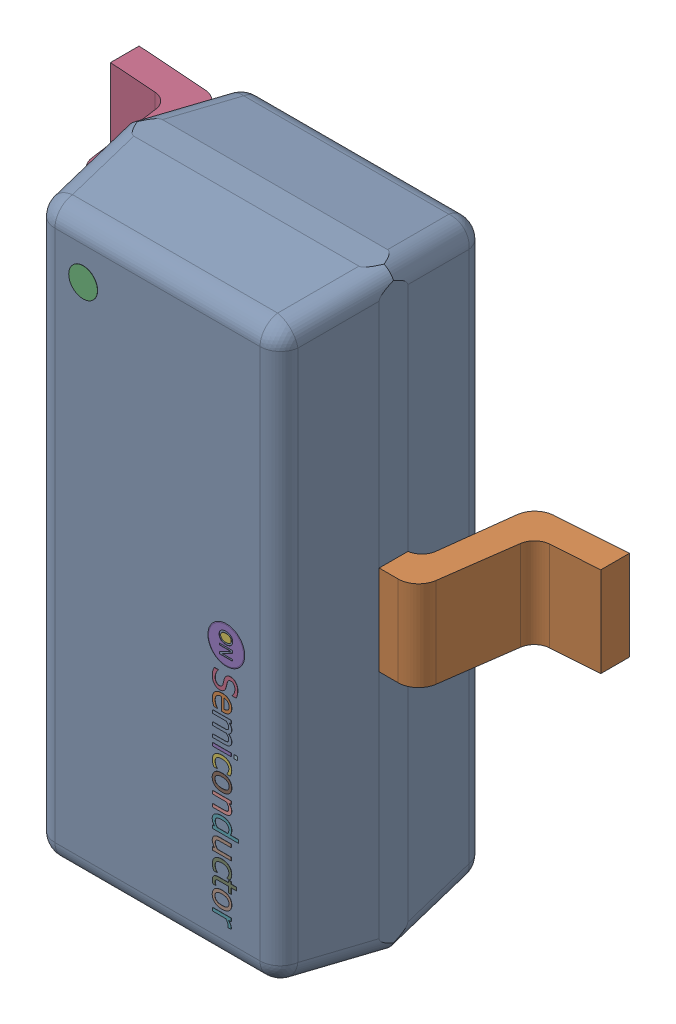
SolidWorks assembly IC_ON_Semiconductor_NUD3112LT1G_eec.step, configuration Default. Lengths in mm.
Overall size (2.4 2.9 1.11).
4 component instances, 4 part files, 0 mates.
Components (placement in the parent):
- 1-5.step-1: 1-5.step [Default] at (0 0 0.1) x (0 1 0) z (0 0 1) size (2.9 1.3 1.01)
- 2-6.step-1: 2-6.step [Default] x (-1 0 0) z (0 1 0) size (2.4 0.68 2.34)
- ON Semi Logo - withoutPN.step-1: ON Semi Logo - withoutPN.step [Default] at (-0.2581 -0.9018 1.011) x (-1 0 0) z (0 0 1) size (0.19 0.19 0.1)
- ON Semi Logo - withoutPN - Copy.step-1: ON Semi Logo - withoutPN - Copy.step [Default] at (-0.2645 -0.8914 1.011) x (-1 0 0) z (0 0 1) size (0.83 2.45 0.1)
